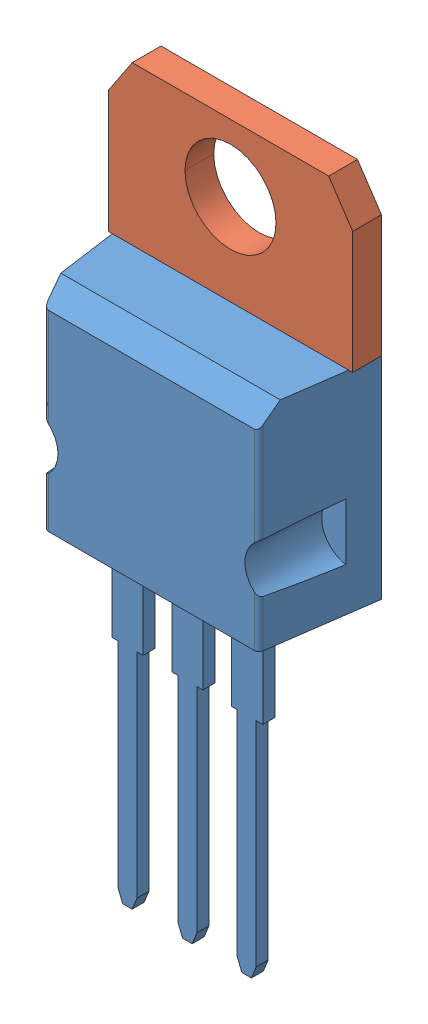
SolidWorks assembly TO 220_BTA16.STEP, configuration Default. Lengths in mm.
Overall size (10.2 28.8 4.5).
2 component instances, 2 part files, 0 mates.
Components (placement in the parent):
- User Library-TO-220-4_Case TO-220___ _________.STEP-1: User Library-TO-220-4_Case TO-220___ _________.STEP [Default] at (16.7891 -23.3398 2.25) size (10.2 22.2 4.5)
- User Library-TO-220-4_Rad Case TO-220___ _________.STEP-1: User Library-TO-220-4_Rad Case TO-220___ _________.STEP [Default] at (21.8891 -20.7398 -2.25) size (10.2 12.8 1.2)
